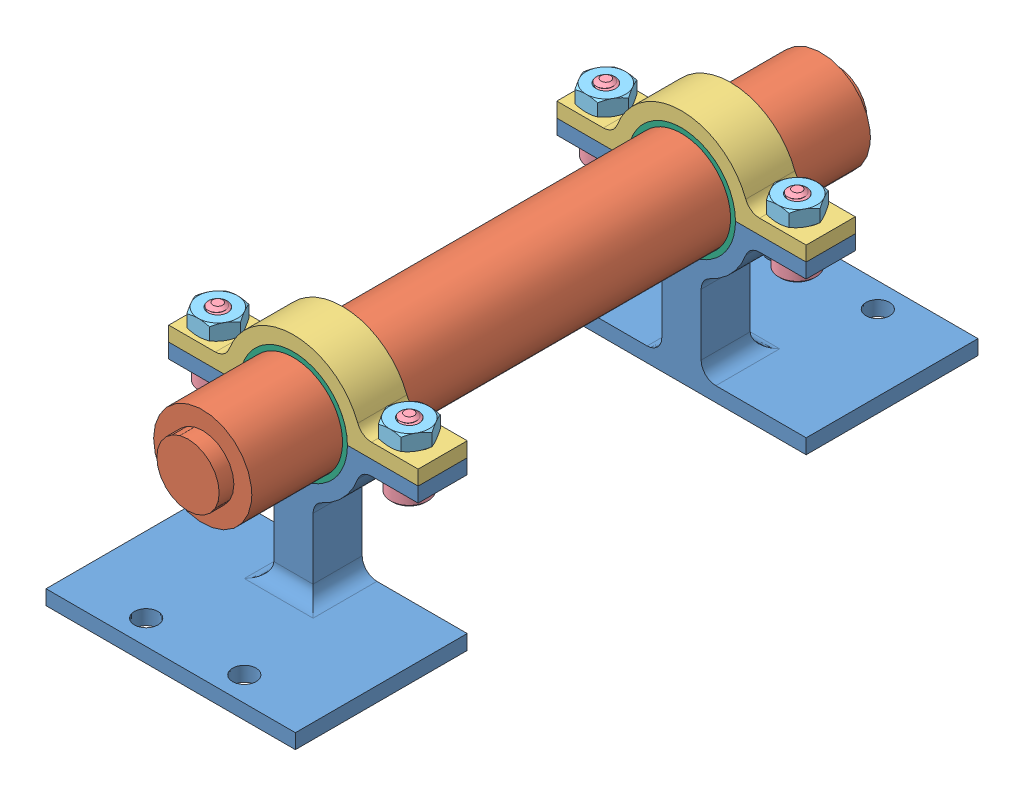
SolidWorks assembly Linear_Short, configuration Default. Lengths in mm.
Overall size (25.79 24 69.52).
15 component instances, 6 part files, 21 mates.
Components (placement in the parent):
- Bracket_Base_Short-1: Bracket_Base_Short [Default] at (-21.8184 10.2694 10.3111) size (25.4 17 17.5)
- Bracket_Base_Short-2: Bracket_Base_Short [Default] at (-21.8184 10.2694 -29.2089) x (-1 0 0) z (0 0 -1) size (25.4 17 17.5)
- Linear_Magnetorquer-1: Linear_Magnetorquer [Default] at (-21.8184 10.2694 -9.4489) size (10 10 66)
- Bracket_Top-1: Bracket_Top [Default] at (-21.8184 10.2694 -29.2089) x (-1 0 0) z (0 0 1) size (25.4 7 5)
- Bracket_Top-2: Bracket_Top [Default] at (-21.8184 10.2694 10.3111) x (-1 0 0) z (0 0 1) size (25.4 7 5)
- 92290A012_TYPE 316 SS SOCKET HEAD CAP SCREW-1: 92290A012_TYPE 316 SS SOCKET HEAD CAP SCREW [92290A012] at (-32.0184 13.7694 10.3111) x (0.961804 0 0.273737) z (0 1 0) size (3.8 3.8 7.44)
- 92290A012_TYPE 316 SS SOCKET HEAD CAP SCREW-2: 92290A012_TYPE 316 SS SOCKET HEAD CAP SCREW [92290A012] at (-32.0184 13.7694 -29.2089) x (0.961804 0 0.273737) z (0 1 0) size (3.8 3.8 7.44)
- 92290A012_TYPE 316 SS SOCKET HEAD CAP SCREW-3: 92290A012_TYPE 316 SS SOCKET HEAD CAP SCREW [92290A012] at (-12.5184 13.7694 10.3111) x (0.961804 0 0.273737) z (0 1 0) size (3.8 3.8 7.44)
- 92290A012_TYPE 316 SS SOCKET HEAD CAP SCREW-4: 92290A012_TYPE 316 SS SOCKET HEAD CAP SCREW [92290A012] at (-12.5184 13.7694 -29.2089) x (0.961804 0 0.273737) z (0 1 0) size (3.8 3.8 7.44)
- 91828A111_TYPE 18-8 STAINLESS STEEL HEX NUT-1: 91828A111_TYPE 18-8 STAINLESS STEEL HEX NUT [91828A111] at (-32.0184 12.5694 10.3111) x (0.866025 0 0.5) z (0 -1 0) size (4 4.62 1.83)
- 91828A111_TYPE 18-8 STAINLESS STEEL HEX NUT-2: 91828A111_TYPE 18-8 STAINLESS STEEL HEX NUT [91828A111] at (-12.5184 12.5694 10.3111) x (0.866025 0 0.5) z (0 -1 0) size (4 4.62 1.83)
- 91828A111_TYPE 18-8 STAINLESS STEEL HEX NUT-3: 91828A111_TYPE 18-8 STAINLESS STEEL HEX NUT [91828A111] at (-32.0184 12.5694 -29.2089) x (0.866025 0 0.5) z (0 -1 0) size (4 4.62 1.83)
- 91828A111_TYPE 18-8 STAINLESS STEEL HEX NUT-4: 91828A111_TYPE 18-8 STAINLESS STEEL HEX NUT [91828A111] at (-12.5184 12.5694 -29.2089) x (0.866025 0 0.5) z (0 -1 0) size (4 4.62 1.83)
- Rubber_grip-1: Rubber_grip [Default] at (-21.8184 10.2694 7.8111) size (11 11 5)
- Rubber_grip-2: Rubber_grip [Default] at (-21.8184 10.2694 -31.7089) size (11 11 5)
Mates (geometry in assembly coordinates):
- Distance1: distance = 34.52 mm anti-aligned: plane of Bracket_Base-1 through (-21.8184 10.2694 7.8111) normal (0 0 -1); plane of Bracket_Base-2 through (-21.8184 10.2694 -26.7089) normal (0 0 1)
- Concentric1: concentric anti-aligned: cylinder of Bracket_Base-2 through (-21.8184 10.2694 -31.7089) axis (0 0 1) radius 5.5; cylinder of Linear_Magnetorquer-1 through (-21.8184 10.2694 22.0511) axis (0 0 -1) radius 5
- Coincident5: coincident anti-aligned: circle of Bracket base-2; circle of Bracket top-1
- Coincident6: coincident anti-aligned: circle of Bracket base-1; circle of Bracket top-2
- Concentric2: concentric anti-aligned: circle of Bracket base-2; circle of Bracket top-1
- Concentric3: concentric anti-aligned: circle of Bracket base-1; circle of Bracket top-2
- Coincident9: coincident anti-aligned: plane of Bracket_Base-1 through (-34.5184 8.7694 12.8111) normal (0 -1 0); plane of 92290A012_TYPE 316 SS SOCKET HEAD CAP SCREW-1 through (-32.0184 8.7694 10.3111) normal (0 1 0)
- Concentric6: concentric aligned: circle of Bracket base-1; circle of 92290A012_TYPE 316 SS SOCKET HEAD CAP SCREW-1
- Parallel1: parallel aligned: plane of Linear_Magnetorquer-1 through (-21.8184 10.2694 -9.4489) normal (1 0 0)
- Coincident12: coincident anti-aligned: plane of Bracket_Top-2 through (-34.5184 11.7694 12.8111) normal (0 1 0); plane of 91828A111_TYPE 18-8 STAINLESS STEEL HEX NUT-1 through (-34.3278 11.7694 10.3111) normal (0 -1 0)
- Concentric10: concentric anti-aligned: circle of Bracket top-2; circle of 91828A111_TYPE 18-8 STAINLESS STEEL HEX NUT-1
- Parallel2: parallel aligned: plane of Bracket_Top-2 through (-21.8184 10.2694 12.8111) normal (0 0 1); plane of 91828A111_TYPE 18-8 STAINLESS STEEL HEX NUT-1 through (-30.8637 11.7694 12.3111) normal (0 0 1)
- Distance4: distance = 10.74 mm aligned: plane of Linear_Magnetorquer-1 through (-21.8184 10.2694 23.5511) normal (0 0 1); plane of Bracket_Base-1 through (-21.8184 10.2694 12.8111) normal (0 0 1)
- Coincident13: coincident aligned: plane of Bracket_Base-1 through (-21.8184 -6.7306 10.3111) normal (0 -1 0); plane of Bracket_Base-2 through (-21.8184 -6.7306 -29.2089) normal (0 -1 0)
- Coincident14: coincident aligned: plane of Bracket_Base-1 through (-9.1184 -6.7306 7.8111) normal (1 0 0); plane of Bracket_Base-2 through (-9.1184 -6.7306 -26.7089) normal (1 0 0)
- Concentric12: concentric aligned: cylinder of Linear_Magnetorquer-1 through (-21.8184 10.2694 22.0511) axis (0 0 -1) radius 5; cylinder of rubber_grip-1 through (-21.8184 10.2694 12.8111) axis (0 0 -1) radius 5.5
- Coincident15: coincident aligned: plane of Bracket_Top-2 through (-21.8184 10.2694 12.8111) normal (0 0 1); plane of rubber_grip-1 through (-21.8184 10.2694 12.8111) normal (0 0 1)
- Concentric13: concentric aligned: cylinder of Linear_Magnetorquer-1 through (-21.8184 10.2694 22.0511) axis (0 0 -1) radius 5; cylinder of rubber_grip-2 through (-21.8184 10.2694 -26.7089) axis (0 0 -1) radius 5
- Coincident16: coincident aligned: plane of Bracket_Top-1 through (-21.8184 10.2694 -31.7089) normal (0 0 -1); plane of rubber_grip-2 through (-21.8184 10.2694 -31.7089) normal (0 0 -1)
- Parallel3: parallel aligned: plane of rubber_grip-1 through (-21.8184 10.2694 7.8111) normal (0 1 0)
- Parallel4: parallel aligned: plane of rubber_grip-2 through (-21.8184 10.2694 -31.7089) normal (0 1 0)
